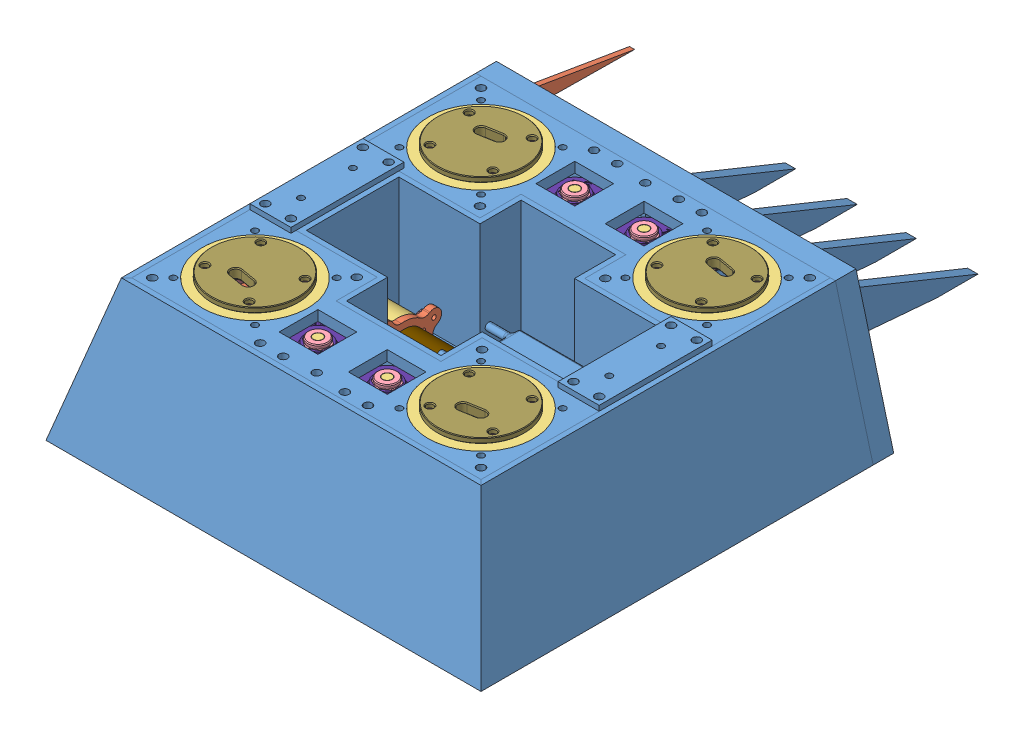
SolidWorks assembly 4WD Swerve Wedge Assembly, configuration Default. Lengths in mm.
Overall size (296.46 104.5 388.68).
183 component instances, 40 part files, 37 mates.
Components (placement in the parent):
- 4WD Swerve Wedge-1: 4WD Swerve Wedge [Default] at origin size (268.87 95.25 382.09)
- Manufacture Ready Swerve_Double Gearbox Wheel_Assem-1: Manufacture Ready Swerve_Double Gearbox Wheel_Assem [Default] at (-69.85 25.4 -69.85) x (-0.171296 0 -0.98522) z (0.98522 0 -0.171296) size (83.94 95.25 79.69)
  - PROPDRIVE 2836-1: PROPDRIVE 2836 [Default] at (-7.34 47.9628 0) x (0 0.80165 -0.597794) z (0 0.597794 0.80165) size (28 45.1 28)
  - Zoro Bearing 50mmID 65mm OD 7mmWidth-1: Zoro Bearing 50mmID 65mm OD 7mmWidth [Default] at (0 63.175 0) x (0.965482 0 -0.260469) z (0.260469 0 0.965482) size (65 7 65)
  - Zoro Bearing 50mmID 65mm OD 7mmWidth-2: Zoro Bearing 50mmID 65mm OD 7mmWidth [Default] at (0 32.075 0) x (0.000165 0 -1) z (1 0 0.000165) size (65 7 65)
  - Double Gearbox 36mm 19 to 1-2: Double Gearbox 36mm 19 to 1 [Default] at (-6.0895 0 0) x (0 0 1) z (0 1 0) size (36 76.01 36)
  - FL696ZZ-1: FL696ZZ [Default] at (30.7875 0 0) x (-1 0 0) z (0 -0.99717 0.07518) size (5 17 17)
  - Casted Swerve Wheel-1: Casted Swerve Wheel [Default] at (-0.4634 0 0) size (26.13 50.8 50.8)
  - Custom Input Shaft Pully-3: Custom Input Shaft Pully [Default] at (20.1995 0 0) x (0 0 1) z (0 1 0) size (19.98 11.18 19.98)
  - 5mm Pully Interface-1: 5mm Pully Interface [Default] at origin size (65.57 21.67 65.57)
  - Bottom Bearing Retainer-1: Bottom Bearing Retainer [Default] at origin size (56.35 4.76 56.35)
  - Drive Motor Face Mount-1: Drive Motor Face Mount [Default] at origin size (2.29 27.26 43.18)
  - Gearbox-Side Support-1: Gearbox-Side Support [Default] at origin size (6.35 34.92 28.57)
  - Inner Modual Lid-1: Inner Modual Lid [Default] at origin size (53.98 6.35 53.98)
  - Innermost Structure-1: Innermost Structure [Default] at origin size (50.34 38.64 53.98)
  - Left Motor Mount Retainer-1: Left Motor Mount Retainer [Default] at origin size (10.68 17.78 8.44)
  - Pully-Side Support-1: Pully-Side Support [Default] at origin size (6.35 34.92 28.57)
  - Wheel Support Mount Plate-1: Wheel Support Mount Plate [Default] at origin size (69.4 4.76 56.35)
  - Left Motor Mount Retainer-2: Left Motor Mount Retainer [Right] at origin size (10.68 17.78 8.44)
  - Custom Motor Output Shaft Pinion-3: Custom Motor Output Shaft Pinion [Default] at (19.431 47.9628 0) x (0 -0.974186 0.225748) z (0 0.225748 0.974186) size (16.43 12.7 16.28)
- 2845 3.17mm 2600kv Surpass-5: 2845 3.17mm 2600kv Surpass [Default] at (-24.11 26.8 0) x (0 -0.462995 0.886361) z (0 -0.886361 -0.462995) size (28 84.78 28)
- OVONIC - 1300mAh - 6S1P-1: OVONIC - 1300mAh - 6S1P [Default] at (41.3 37.465 -21.2725) x (0 1 0) z (1 0 0) size (36.86 42.55 90.17)
- 36mm 47.1(263_1) gear box-1: 36mm 47.1(263_1) gear box [Default] at (-51.547 26.8 0) x (0 0.509483 -0.860481) z (0 0.860481 0.509483) size (52.63 77.16 52.63)
  - 251916mount_36mm gearbox.step-1: 251916mount_36mm gearbox.step [Default] at (0 2.413 0) size (52.63 6.35 52.63)
  - 36mm 47.1(263_1) gear box.step-1: 36mm 47.1(263_1) gear box.step [Default] at origin size (36 45.1 36)
  - 36mm 47.1(263_1) gear box-0.step-1: 36mm 47.1(263_1) gear box-0.step [Default] at origin size (36 10.13 36)
  - 36mm 47.1(263_1) gear box-1.step-1: 36mm 47.1(263_1) gear box-1.step [Default] at origin size (8 20 8)
- Manufacture Ready Swerve_Double Gearbox Wheel_Assem-6: Manufacture Ready Swerve_Double Gearbox Wheel_Assem [Default] at (69.85 25.4 69.85) x (0.171296 0 0.98522) z (-0.98522 0 0.171296) size (83.94 95.25 79.69)
  - PROPDRIVE 2836-1: PROPDRIVE 2836 [Default] at (-7.34 47.9628 0) x (0 0.80165 -0.597794) z (0 0.597794 0.80165) size (28 45.1 28)
  - Zoro Bearing 50mmID 65mm OD 7mmWidth-1: Zoro Bearing 50mmID 65mm OD 7mmWidth [Default] at (0 63.175 0) x (0.965482 0 -0.260469) z (0.260469 0 0.965482) size (65 7 65)
  - Zoro Bearing 50mmID 65mm OD 7mmWidth-2: Zoro Bearing 50mmID 65mm OD 7mmWidth [Default] at (0 32.075 0) x (0.000165 0 -1) z (1 0 0.000165) size (65 7 65)
  - Double Gearbox 36mm 19 to 1-2: Double Gearbox 36mm 19 to 1 [Default] at (-6.0895 0 0) x (0 0 1) z (0 1 0) size (36 76.01 36)
  - FL696ZZ-1: FL696ZZ [Default] at (30.7875 0 0) x (-1 0 0) z (0 -0.99717 0.07518) size (5 17 17)
  - Casted Swerve Wheel-1: Casted Swerve Wheel [Default] at (-0.4634 0 0) size (26.13 50.8 50.8)
  - Custom Input Shaft Pully-3: Custom Input Shaft Pully [Default] at (20.1995 0 0) x (0 0 1) z (0 1 0) size (19.98 11.18 19.98)
  - 5mm Pully Interface-1: 5mm Pully Interface [Default] at origin size (65.57 21.67 65.57)
  - Bottom Bearing Retainer-1: Bottom Bearing Retainer [Default] at origin size (56.35 4.76 56.35)
  - Drive Motor Face Mount-1: Drive Motor Face Mount [Default] at origin size (2.29 27.26 43.18)
  - Gearbox-Side Support-1: Gearbox-Side Support [Default] at origin size (6.35 34.92 28.57)
  - Inner Modual Lid-1: Inner Modual Lid [Default] at origin size (53.98 6.35 53.98)
  - Innermost Structure-1: Innermost Structure [Default] at origin size (50.34 38.64 53.98)
  - Left Motor Mount Retainer-1: Left Motor Mount Retainer [Default] at origin size (10.68 17.78 8.44)
  - Pully-Side Support-1: Pully-Side Support [Default] at origin size (6.35 34.92 28.57)
  - Wheel Support Mount Plate-1: Wheel Support Mount Plate [Default] at origin size (69.4 4.76 56.35)
  - Left Motor Mount Retainer-2: Left Motor Mount Retainer [Right] at origin size (10.68 17.78 8.44)
  - Custom Motor Output Shaft Pinion-3: Custom Motor Output Shaft Pinion [Default] at (19.431 47.9628 0) x (0 -0.974186 0.225748) z (0 0.225748 0.974186) size (16.43 12.7 16.28)
- DartBox V2 6mm Shaft-1: DartBox V2 6mm Shaft [Default] at (-6.022 -10.937 -80.2176) x (-0.054657 0 -0.998505) z (0 1 0) size (21.95 21.95 72.3)
  - DartBox V2 6mm Shaft.stp-1: DartBox V2 6mm Shaft.stp [Default] at origin size (21.95 21.95 72.3)
    - DartBox V2 Drive 6mm Output.stp-1: DartBox V2 Drive 6mm Output.stp [Default] at (0 15.4164 54.362) x (0 1 0) z (0 0 1) size (21.95 21.95 42.9)
      - Ring Gear.stp-1: Ring Gear.stp [Default] at (-10.101 0.0152 -54.1116) x (0 -1 0) z (0 0 1) size (21.95 21.95 40.4)
        - Front Plate.stp-1: Front Plate.stp [Default] at (0.0152 10.101 56.6116) x (0 1 0) z (1 0 0) size (21.95 30.5 21.95)
          - Shaft.stp-1: Shaft.stp [Default] x (-0.819152 0 -0.573576) z (0.573576 0 -0.819152) size (7.4 30.3 6.7)
            - Retaining Ring.stp-1: Retaining Ring.stp [Default] at (0 16.65 0) x (-1 0 0) z (0 -1 0) size (7.4 6.16 0.5)
            - Shaft-0.stp-1: Shaft-0.stp [Default] at origin size (6 30.3 6)
          - Front Plate-1.stp-1: Front Plate-1.stp [Default] at origin size (21.95 6.5 21.95)
          - Front Plate-2.stp-1: Front Plate-2.stp [Default] at origin size (9.5 6 9.5)
        - Ring Gear Body.stp-1: Ring Gear Body.stp [Default] at (0.0152 10.101 56.6116) x (0 1 0) z (1 0 0) size (16.5 10.4 16.5)
      - Motor Mount Plate.stp-1: Motor Mount Plate.stp [Default] at (0 0 2.5) x (1 0 0) z (0 -1 0) size (21.95 3.5 21.95)
      - Screws M2 x 14mm.stp-1: Screws M2 x 14mm.stp [Default] at (6.364 6.364 0.9) size (3.4 3.4 15.61)
      - Screws M2 x 14mm.stp-2: Screws M2 x 14mm.stp [Default] at (-6.364 6.364 0.9) x (0 1 0) z (0 0 1) size (3.4 3.4 15.61)
      - Screws M2 x 14mm.stp-3: Screws M2 x 14mm.stp [Default] at (-6.364 -6.364 0.9) x (-1 0 0) z (0 0 1) size (3.4 3.4 15.61)
      - Screws M2 x 14mm.stp-4: Screws M2 x 14mm.stp [Default] at (6.364 -6.364 0.9) x (0 -1 0) z (0 0 1) size (3.4 3.4 15.61)
    - DartBox 130 motor.stp-1: DartBox 130 motor.stp [Default] at (0 15.4164 54.362) x (1 0 0) z (0 0 -1) size (15.5 20.4 34.9)
- Manufacture Ready Swerve_Double Gearbox Wheel_Assem-8: Manufacture Ready Swerve_Double Gearbox Wheel_Assem [Default] at (69.85 25.4 -69.85) x (0.171296 0 -0.98522) z (0.98522 0 0.171296) size (83.94 95.25 79.69)
  - PROPDRIVE 2836-1: PROPDRIVE 2836 [Default] at (-7.34 47.9628 0) x (0 0.80165 -0.597794) z (0 0.597794 0.80165) size (28 45.1 28)
  - Zoro Bearing 50mmID 65mm OD 7mmWidth-1: Zoro Bearing 50mmID 65mm OD 7mmWidth [Default] at (0 63.175 0) x (0.965482 0 -0.260469) z (0.260469 0 0.965482) size (65 7 65)
  - Zoro Bearing 50mmID 65mm OD 7mmWidth-2: Zoro Bearing 50mmID 65mm OD 7mmWidth [Default] at (0 32.075 0) x (0.000165 0 -1) z (1 0 0.000165) size (65 7 65)
  - Double Gearbox 36mm 19 to 1-2: Double Gearbox 36mm 19 to 1 [Default] at (-6.0895 0 0) x (0 0 1) z (0 1 0) size (36 76.01 36)
  - FL696ZZ-1: FL696ZZ [Default] at (30.7875 0 0) x (-1 0 0) z (0 -0.99717 0.07518) size (5 17 17)
  - Casted Swerve Wheel-1: Casted Swerve Wheel [Default] at (-0.4634 0 0) size (26.13 50.8 50.8)
  - Custom Input Shaft Pully-3: Custom Input Shaft Pully [Default] at (20.1995 0 0) x (0 0 1) z (0 1 0) size (19.98 11.18 19.98)
  - 5mm Pully Interface-1: 5mm Pully Interface [Default] at origin size (65.57 21.67 65.57)
  - Bottom Bearing Retainer-1: Bottom Bearing Retainer [Default] at origin size (56.35 4.76 56.35)
  - Drive Motor Face Mount-1: Drive Motor Face Mount [Default] at origin size (2.29 27.26 43.18)
  - Gearbox-Side Support-1: Gearbox-Side Support [Default] at origin size (6.35 34.92 28.57)
  - Inner Modual Lid-1: Inner Modual Lid [Default] at origin size (53.98 6.35 53.98)
  - Innermost Structure-1: Innermost Structure [Default] at origin size (50.34 38.64 53.98)
  - Left Motor Mount Retainer-1: Left Motor Mount Retainer [Default] at origin size (10.68 17.78 8.44)
  - Pully-Side Support-1: Pully-Side Support [Default] at origin size (6.35 34.92 28.57)
  - Wheel Support Mount Plate-1: Wheel Support Mount Plate [Default] at origin size (69.4 4.76 56.35)
  - Left Motor Mount Retainer-2: Left Motor Mount Retainer [Right] at origin size (10.68 17.78 8.44)
  - Custom Motor Output Shaft Pinion-3: Custom Motor Output Shaft Pinion [Default] at (19.431 47.9628 0) x (0 -0.974186 0.225748) z (0 0.225748 0.974186) size (16.43 12.7 16.28)
- DartBox V2 6mm Shaft-2: DartBox V2 6mm Shaft [Default] at (36.8087 -10.937 -78.5324) x (0.054657 0 -0.998505) z (0 1 0) size (21.95 21.95 72.3)
  - DartBox V2 6mm Shaft.stp-1: DartBox V2 6mm Shaft.stp [Default] at origin size (21.95 21.95 72.3)
    - DartBox V2 Drive 6mm Output.stp-1: DartBox V2 Drive 6mm Output.stp [Default] at (0 15.4164 54.362) x (0 1 0) z (0 0 1) size (21.95 21.95 42.9)
      - Ring Gear.stp-1: Ring Gear.stp [Default] at (-10.101 0.0152 -54.1116) x (0 -1 0) z (0 0 1) size (21.95 21.95 40.4)
        - Front Plate.stp-1: Front Plate.stp [Default] at (0.0152 10.101 56.6116) x (0 1 0) z (1 0 0) size (21.95 30.5 21.95)
          - Shaft.stp-1: Shaft.stp [Default] x (-0.819152 0 -0.573576) z (0.573576 0 -0.819152) size (7.4 30.3 6.7)
            - Retaining Ring.stp-1: Retaining Ring.stp [Default] at (0 16.65 0) x (-1 0 0) z (0 -1 0) size (7.4 6.16 0.5)
            - Shaft-0.stp-1: Shaft-0.stp [Default] at origin size (6 30.3 6)
          - Front Plate-1.stp-1: Front Plate-1.stp [Default] at origin size (21.95 6.5 21.95)
          - Front Plate-2.stp-1: Front Plate-2.stp [Default] at origin size (9.5 6 9.5)
        - Ring Gear Body.stp-1: Ring Gear Body.stp [Default] at (0.0152 10.101 56.6116) x (0 1 0) z (1 0 0) size (16.5 10.4 16.5)
      - Motor Mount Plate.stp-1: Motor Mount Plate.stp [Default] at (0 0 2.5) x (1 0 0) z (0 -1 0) size (21.95 3.5 21.95)
      - Screws M2 x 14mm.stp-1: Screws M2 x 14mm.stp [Default] at (6.364 6.364 0.9) size (3.4 3.4 15.61)
      - Screws M2 x 14mm.stp-2: Screws M2 x 14mm.stp [Default] at (-6.364 6.364 0.9) x (0 1 0) z (0 0 1) size (3.4 3.4 15.61)
      - Screws M2 x 14mm.stp-3: Screws M2 x 14mm.stp [Default] at (-6.364 -6.364 0.9) x (-1 0 0) z (0 0 1) size (3.4 3.4 15.61)
      - Screws M2 x 14mm.stp-4: Screws M2 x 14mm.stp [Default] at (6.364 -6.364 0.9) x (0 -1 0) z (0 0 1) size (3.4 3.4 15.61)
    - DartBox 130 motor.stp-1: DartBox 130 motor.stp [Default] at (0 15.4164 54.362) x (1 0 0) z (0 0 -1) size (15.5 20.4 34.9)
- Manufacture Ready Swerve_Double Gearbox Wheel_Assem-9: Manufacture Ready Swerve_Double Gearbox Wheel_Assem [Default] at (-69.85 25.4 69.85) x (-0.171296 0 0.98522) z (-0.98522 0 -0.171296) size (83.94 95.25 79.69)
  - PROPDRIVE 2836-1: PROPDRIVE 2836 [Default] at (-7.34 47.9628 0) x (0 0.80165 -0.597794) z (0 0.597794 0.80165) size (28 45.1 28)
  - Zoro Bearing 50mmID 65mm OD 7mmWidth-1: Zoro Bearing 50mmID 65mm OD 7mmWidth [Default] at (0 63.175 0) x (0.965482 0 -0.260469) z (0.260469 0 0.965482) size (65 7 65)
  - Zoro Bearing 50mmID 65mm OD 7mmWidth-2: Zoro Bearing 50mmID 65mm OD 7mmWidth [Default] at (0 32.075 0) x (0.000165 0 -1) z (1 0 0.000165) size (65 7 65)
  - Double Gearbox 36mm 19 to 1-2: Double Gearbox 36mm 19 to 1 [Default] at (-6.0895 0 0) x (0 0 1) z (0 1 0) size (36 76.01 36)
  - FL696ZZ-1: FL696ZZ [Default] at (30.7875 0 0) x (-1 0 0) z (0 -0.99717 0.07518) size (5 17 17)
  - Casted Swerve Wheel-1: Casted Swerve Wheel [Default] at (-0.4634 0 0) size (26.13 50.8 50.8)
  - Custom Input Shaft Pully-3: Custom Input Shaft Pully [Default] at (20.1995 0 0) x (0 0 1) z (0 1 0) size (19.98 11.18 19.98)
  - 5mm Pully Interface-1: 5mm Pully Interface [Default] at origin size (65.57 21.67 65.57)
  - Bottom Bearing Retainer-1: Bottom Bearing Retainer [Default] at origin size (56.35 4.76 56.35)
  - Drive Motor Face Mount-1: Drive Motor Face Mount [Default] at origin size (2.29 27.26 43.18)
  - Gearbox-Side Support-1: Gearbox-Side Support [Default] at origin size (6.35 34.92 28.57)
  - Inner Modual Lid-1: Inner Modual Lid [Default] at origin size (53.98 6.35 53.98)
  - Innermost Structure-1: Innermost Structure [Default] at origin size (50.34 38.64 53.98)
  - Left Motor Mount Retainer-1: Left Motor Mount Retainer [Default] at origin size (10.68 17.78 8.44)
  - Pully-Side Support-1: Pully-Side Support [Default] at origin size (6.35 34.92 28.57)
  - Wheel Support Mount Plate-1: Wheel Support Mount Plate [Default] at origin size (69.4 4.76 56.35)
  - Left Motor Mount Retainer-2: Left Motor Mount Retainer [Right] at origin size (10.68 17.78 8.44)
  - Custom Motor Output Shaft Pinion-3: Custom Motor Output Shaft Pinion [Default] at (19.431 47.9628 0) x (0 -0.974186 0.225748) z (0 0.225748 0.974186) size (16.43 12.7 16.28)
- DartBox V2 6mm Shaft-3: DartBox V2 6mm Shaft [Default] at (-36.8087 -10.937 78.5324) x (-0.054657 0 0.998505) z (0 1 0) size (21.95 21.95 72.3)
  - DartBox V2 6mm Shaft.stp-1: DartBox V2 6mm Shaft.stp [Default] at origin size (21.95 21.95 72.3)
    - DartBox V2 Drive 6mm Output.stp-1: DartBox V2 Drive 6mm Output.stp [Default] at (0 15.4164 54.362) x (0 1 0) z (0 0 1) size (21.95 21.95 42.9)
      - Ring Gear.stp-1: Ring Gear.stp [Default] at (-10.101 0.0152 -54.1116) x (0 -1 0) z (0 0 1) size (21.95 21.95 40.4)
        - Front Plate.stp-1: Front Plate.stp [Default] at (0.0152 10.101 56.6116) x (0 1 0) z (1 0 0) size (21.95 30.5 21.95)
          - Shaft.stp-1: Shaft.stp [Default] x (-0.819152 0 -0.573576) z (0.573576 0 -0.819152) size (7.4 30.3 6.7)
            - Retaining Ring.stp-1: Retaining Ring.stp [Default] at (0 16.65 0) x (-1 0 0) z (0 -1 0) size (7.4 6.16 0.5)
            - Shaft-0.stp-1: Shaft-0.stp [Default] at origin size (6 30.3 6)
          - Front Plate-1.stp-1: Front Plate-1.stp [Default] at origin size (21.95 6.5 21.95)
          - Front Plate-2.stp-1: Front Plate-2.stp [Default] at origin size (9.5 6 9.5)
        - Ring Gear Body.stp-1: Ring Gear Body.stp [Default] at (0.0152 10.101 56.6116) x (0 1 0) z (1 0 0) size (16.5 10.4 16.5)
      - Motor Mount Plate.stp-1: Motor Mount Plate.stp [Default] at (0 0 2.5) x (1 0 0) z (0 -1 0) size (21.95 3.5 21.95)
      - Screws M2 x 14mm.stp-1: Screws M2 x 14mm.stp [Default] at (6.364 6.364 0.9) size (3.4 3.4 15.61)
      - Screws M2 x 14mm.stp-2: Screws M2 x 14mm.stp [Default] at (-6.364 6.364 0.9) x (0 1 0) z (0 0 1) size (3.4 3.4 15.61)
      - Screws M2 x 14mm.stp-3: Screws M2 x 14mm.stp [Default] at (-6.364 -6.364 0.9) x (-1 0 0) z (0 0 1) size (3.4 3.4 15.61)
      - Screws M2 x 14mm.stp-4: Screws M2 x 14mm.stp [Default] at (6.364 -6.364 0.9) x (0 -1 0) z (0 0 1) size (3.4 3.4 15.61)
    - DartBox 130 motor.stp-1: DartBox 130 motor.stp [Default] at (0 15.4164 54.362) x (1 0 0) z (0 0 -1) size (15.5 20.4 34.9)
- DartBox V2 6mm Shaft-4: DartBox V2 6mm Shaft [Default] at (6.022 -10.937 80.2176) x (0.054657 0 0.998505) z (0 1 0) size (21.95 21.95 72.3)
  - DartBox V2 6mm Shaft.stp-1: DartBox V2 6mm Shaft.stp [Default] at origin size (21.95 21.95 72.3)
    - DartBox V2 Drive 6mm Output.stp-1: DartBox V2 Drive 6mm Output.stp [Default] at (0 15.4164 54.362) x (0 1 0) z (0 0 1) size (21.95 21.95 42.9)
      - Ring Gear.stp-1: Ring Gear.stp [Default] at (-10.101 0.0152 -54.1116) x (0 -1 0) z (0 0 1) size (21.95 21.95 40.4)
        - Front Plate.stp-1: Front Plate.stp [Default] at (0.0152 10.101 56.6116) x (0 1 0) z (1 0 0) size (21.95 30.5 21.95)
          - Shaft.stp-1: Shaft.stp [Default] x (-0.819152 0 -0.573576) z (0.573576 0 -0.819152) size (7.4 30.3 6.7)
            - Retaining Ring.stp-1: Retaining Ring.stp [Default] at (0 16.65 0) x (-1 0 0) z (0 -1 0) size (7.4 6.16 0.5)
            - Shaft-0.stp-1: Shaft-0.stp [Default] at origin size (6 30.3 6)
          - Front Plate-1.stp-1: Front Plate-1.stp [Default] at origin size (21.95 6.5 21.95)
          - Front Plate-2.stp-1: Front Plate-2.stp [Default] at origin size (9.5 6 9.5)
        - Ring Gear Body.stp-1: Ring Gear Body.stp [Default] at (0.0152 10.101 56.6116) x (0 1 0) z (1 0 0) size (16.5 10.4 16.5)
      - Motor Mount Plate.stp-1: Motor Mount Plate.stp [Default] at (0 0 2.5) x (1 0 0) z (0 -1 0) size (21.95 3.5 21.95)
      - Screws M2 x 14mm.stp-1: Screws M2 x 14mm.stp [Default] at (6.364 6.364 0.9) size (3.4 3.4 15.61)
      - Screws M2 x 14mm.stp-2: Screws M2 x 14mm.stp [Default] at (-6.364 6.364 0.9) x (0 1 0) z (0 0 1) size (3.4 3.4 15.61)
      - Screws M2 x 14mm.stp-3: Screws M2 x 14mm.stp [Default] at (-6.364 -6.364 0.9) x (-1 0 0) z (0 0 1) size (3.4 3.4 15.61)
      - Screws M2 x 14mm.stp-4: Screws M2 x 14mm.stp [Default] at (6.364 -6.364 0.9) x (0 -1 0) z (0 0 1) size (3.4 3.4 15.61)
    - DartBox 130 motor.stp-1: DartBox 130 motor.stp [Default] at (0 15.4164 54.362) x (1 0 0) z (0 0 -1) size (15.5 20.4 34.9)
- 36mm goBILDA motor clamp-1: 36mm goBILDA motor clamp [Default] at (-83.0172 32.3593 -30.3345) x (0 0 -1) z (-1 0 0) size (46.17 45 8)
  - 1400-0032-0036.STEP-1: 1400-0032-0036.STEP [Default] at (-30.3345 5.5593 8.2328) size (46.17 45 8)
  - 2800-0004-0012_90128A207.STEP-1: 2800-0004-0012_90128A207.STEP [Default] at (-8.6623 -1.4407 12.2328) x (1 0 0) z (0 -1 0) size (7 7 16.01)
- RB Standoff_-1: RB Standoff_ [1000L] at (-103.1875 73.025 -30.1625) size (9.53 25.4 9.53)
- RB Standoff_-2: RB Standoff_ [1000L] at (-87.3125 73.025 -30.1625) size (9.53 25.4 9.53)
- RB Standoff_-3: RB Standoff_ [1000L] at (87.3125 73.025 -30.1625) x (-1 0 0) z (0 0 -1) size (9.53 25.4 9.53)
- RB Standoff_-4: RB Standoff_ [1000L] at (103.1875 73.025 -30.1625) x (-1 0 0) z (0 0 -1) size (9.53 25.4 9.53)
- RB Standoff_-5: RB Standoff_ [1000L] at (103.1875 73.025 30.1625) x (-1 0 0) z (0 0 -1) size (9.53 25.4 9.53)
- RB Standoff_-6: RB Standoff_ [1000L] at (87.3125 73.025 30.1625) x (-1 0 0) z (0 0 -1) size (9.53 25.4 9.53)
- RB Standoff_-7: RB Standoff_ [1000L] at (-87.3125 73.025 30.1625) size (9.53 25.4 9.53)
- RB Standoff_-8: RB Standoff_ [1000L] at (-103.1875 73.025 30.1625) size (9.53 25.4 9.53)
- Proto Swerve Turn Pinion 5mm HTD Pulley-1: Proto Swerve Turn Pinion 5mm HTD Pulley [Default] at (-21.4153 73.9232 -79.375) x (0.825312 0 -0.564678) z (0.564678 0 0.825312) size (31.44 23.6 31.44)
- Proto Swerve Turn Pinion 5mm HTD Pulley-2: Proto Swerve Turn Pinion 5mm HTD Pulley [Default] at (21.4153 73.9232 -79.375) x (0.825312 0 0.564678) z (-0.564678 0 0.825312) size (31.44 23.6 31.44)
- Proto Swerve Turn Pinion 5mm HTD Pulley-3: Proto Swerve Turn Pinion 5mm HTD Pulley [Default] at (21.4153 73.9232 79.375) x (-0.825312 0 0.564678) z (-0.564678 0 -0.825312) size (31.44 23.6 31.44)
- Proto Swerve Turn Pinion 5mm HTD Pulley-4: Proto Swerve Turn Pinion 5mm HTD Pulley [Default] at (-21.4153 73.9232 79.375) x (-0.825312 0 -0.564678) z (0.564678 0 -0.825312) size (31.44 23.6 31.44)
- RB Standoff_-11: RB Standoff_ [1000L] at (-38.7415 73.025 -38.1) x (0.918365 0 -0.395734) z (0.395734 0 0.918365) size (9.53 25.4 9.53)
- RB Standoff_-14: RB Standoff_ [1000L] at (38.7415 73.025 -38.1) x (-0.918365 0 -0.395734) z (0.395734 0 -0.918365) size (9.53 25.4 9.53)
- RB Standoff_-17: RB Standoff_ [1000L] at (-38.7415 73.025 38.1) x (0.918365 0 0.395734) z (-0.395734 0 0.918365) size (9.53 25.4 9.53)
- RB Standoff_-19: RB Standoff_ [1000L] at (38.7415 73.025 38.1) x (-0.918365 0 0.395734) z (-0.395734 0 -0.918365) size (9.53 25.4 9.53)
- T81H-RM41.stp-1: T81H-RM41.stp [Default] at (-113.125 26.8 0) x (0 0.870146 -0.492795) z (-1 0 0) size (20.32 20.32 20.32)
- 0.375in_Medium_NutStrip_2x2_R1.step_Custom-1: 0.375in_Medium_NutStrip_2x2_R1.step_Custom [Default] at (14.2875 49.2125 -103.1875) x (0 0 1) z (-1 0 0) size (9.53 9.53 28.97)
- 0.375in_Medium_NutStrip_2x2_R1.step_Custom-2: 0.375in_Medium_NutStrip_2x2_R1.step_Custom [Default] at (-14.2875 49.2125 -103.1875) x (0 0 -1) z (1 0 0) size (9.53 9.53 28.97)
- 4wd Swerve Finger-1: 4wd Swerve Finger [Default] at (-115.665 26.8 0) x (0 0.011579 0.999933) z (0 -0.999933 0.011579) size (276.45 46.36 44.9)
- AS5600 Encoder Magnet-1: AS5600 Encoder Magnet [Default] at (-21.4153 88.2942 -79.375) size (6 2.5 6)
- Custom Motor Output Shaft-1: Custom Motor Output Shaft [Default] at (-21.4153 76.2346 -79.375) x (0.432402 0 -0.901681) z (0 -1 0) size (12.7 13.75 26.62)
- Custom Motor Output Shaft-2: Custom Motor Output Shaft [Default] at (21.4153 76.2346 -79.375) x (-0.432402 0 -0.901681) z (0 1 0) size (12.7 13.75 26.62)
- AS5600 Encoder Magnet-2: AS5600 Encoder Magnet [Default] at (21.4153 88.2942 -79.375) x (-1 0 0) z (0 0 -1) size (6 2.5 6)
- AS5600 Encoder Magnet-3: AS5600 Encoder Magnet [Default] at (-21.4153 88.2942 79.375) size (6 2.5 6)
- Custom Motor Output Shaft-3: Custom Motor Output Shaft [Default] at (-21.4153 76.2346 79.375) x (0.432402 0 0.901681) z (0 1 0) size (12.7 13.75 26.62)
- AS5600 Encoder Magnet-4: AS5600 Encoder Magnet [Default] at (21.4153 88.2942 79.375) x (-1 0 0) z (0 0 -1) size (6 2.5 6)
- Custom Motor Output Shaft-4: Custom Motor Output Shaft [Default] at (21.4153 76.2346 79.375) x (-0.432402 0 0.901681) z (0 -1 0) size (12.7 13.75 26.62)
Mates (geometry in assembly coordinates):
- Coincident1: coincident aligned: plane of 4WD Swerve Wedge-1 through (0 0 0) normal (0 0 1)
- Coincident2: coincident aligned: plane of 4WD Swerve Wedge-1 through (0 0 0) normal (0 1 0)
- Coincident3: coincident aligned: plane of 4WD Swerve Wedge-1 through (0 0 0) normal (1 0 0)
- Coincident4: coincident aligned: plane of 4WD Swerve Wedge-1 through (0 92.075 0) normal (0 1 0); plane of Manufacture Ready Swerve_Double Gearbox Wheel_Assem-1/Zoro Bearing 50mmID 65mm OD 7mmWidth-1 through (-69.85 92.075 -69.85) normal (0 1 0)
- Concentric1: concentric anti-aligned: cylinder of 4WD Swerve Wedge-1 through (-69.85 85.725 -69.85) axis (0 1 0) radius 32.5; cylinder of Manufacture Ready Swerve_Double Gearbox Wheel_Assem-1/Zoro Bearing 50mmID 65mm OD 7mmWidth-1 through (-69.85 92.075 -69.85) axis (0 -1 0) radius 32.5
- Coincident10: coincident anti-aligned: plane of 2845 3.17mm 2600kv Surpass-5 through (-47.61 26.8 0) normal (-1 0 0); plane of 36mm 47.1(263_1) gear box-1/251916mount_36mm gearbox.step-1 through (-47.61 26.8 0) normal (1 0 0)
- Concentric3: concentric aligned: cylinder of 2845 3.17mm 2600kv Surpass-5 through (-24.11 26.8 0) axis (-1 0 0) radius 14; cylinder of 36mm 47.1(263_1) gear box-1/36mm 47.1(263_1) gear box.step-1 through (-51.547 26.8 0) axis (-1 0 0) radius 18
- Coincident12: coincident: line of 4WD Swerve Wedge-1 through (-104.775 0 14.825) axis (0 0 -1); plane of 36mm 47.1(263_1) gear box-1/36mm 47.1(263_1) gear box-0.step-1 through (-104.775 26.8 0) normal (-1 0 0)
- Coincident18: coincident aligned: plane of 4WD Swerve Wedge-1 through (0 60.325 0) normal (0 1 0); plane of DartBox V2 6mm Shaft-1/DartBox V2 6mm Shaft.stp-1/DartBox V2 Drive 6mm Output.stp-1/Ring Gear.stp-1/Front Plate.stp-1/Front Plate-1.stp-1 through (-21.4153 60.325 -79.375) normal (0 1 0)
- Concentric6: concentric aligned: cylinder of DartBox V2 6mm Shaft-1/DartBox V2 6mm Shaft.stp-1/DartBox V2 Drive 6mm Output.stp-1/Ring Gear.stp-1/Front Plate.stp-1/Front Plate-1.stp-1 through (-21.4153 56.325 -79.375) axis (0 1 0) radius 10.975; cylinder of 4WD Swerve Wedge-1 through (-21.4153 53.975 -79.375) axis (0 1 0) radius 10.9728
- Coincident19: coincident anti-aligned: plane of 4WD Swerve Wedge-1 through (0 50.8 0) normal (0 -1 0); plane of 36mm goBILDA motor clamp-1/1400-0032-0036.STEP-1 through (-99.25 50.8 19) normal (0 1 0)
- Concentric7: concentric anti-aligned: cylinder of 4WD Swerve Wedge-1 through (-95.25 92.076 16) axis (0 -1 0) radius 2; cylinder of 36mm goBILDA motor clamp-1/1400-0032-0036.STEP-1 through (-95.25 50.8 16) axis (0 1 0) radius 1.65
- Concentric8: concentric aligned: cylinder of 4WD Swerve Wedge-1 through (-95.25 53.974 -16) axis (0 1 0) radius 2; cylinder of 36mm goBILDA motor clamp-1/1400-0032-0036.STEP-1 through (-95.25 50.8 -16) axis (0 1 0) radius 1.65
- Concentric9: concentric anti-aligned: cylinder of 36mm 47.1(263_1) gear box-1/36mm 47.1(263_1) gear box.step-1 through (-51.547 26.8 0) axis (-1 0 0) radius 18; cylinder of 36mm goBILDA motor clamp-1/1400-0032-0036.STEP-1 through (-99.25 26.8 0) axis (1 0 0) radius 18
- Distance1: distance = 3.175 mm anti-aligned: plane of OVONIC - 1300mAh - 6S1P-1 through (2.565 19.05 21.2725) normal (-1 0 0); plane of 2845 3.17mm 2600kv Surpass-5 through (-0.61 26.8 0) normal (1 0 0)
- Width1: width aligned: plane of OVONIC - 1300mAh - 6S1P-1 through (41.3 37.465 21.2725) normal (0 0 1); plane of 4WD Swerve Wedge-1 through (41.3 37.465 -21.2725) normal (0 0 -1); plane of OVONIC - 1300mAh - 6S1P-1 through (-107.95 60.325 -31.75) normal (0 0 1); plane of 4WD Swerve Wedge-1 through (107.95 60.325 31.75) normal (0 0 -1)
- Concentric10: concentric aligned: cylinder of 4WD Swerve Wedge-1 through (-103.1875 50.8 -30.1625) axis (0 -1 0) radius 2.5527; cylinder of RB Standoff_-1 through (-103.1875 85.725 -30.1625) axis (0 -1 0) radius 4.7625
- Coincident22: coincident anti-aligned: plane of 4WD Swerve Wedge-1 through (0 60.325 0) normal (0 1 0); plane of RB Standoff_-1 through (-103.1875 60.325 -30.1625) normal (0 -1 0)
- Concentric11: concentric aligned: cylinder of 4WD Swerve Wedge-1 through (-87.3125 50.8 -30.1625) axis (0 -1 0) radius 2.5527; cylinder of RB Standoff_-2 through (-87.3125 85.725 -30.1625) axis (0 -1 0) radius 4.7625
- Coincident23: coincident anti-aligned: plane of 4WD Swerve Wedge-1 through (0 60.325 0) normal (0 1 0); plane of RB Standoff_-2 through (-87.3125 60.325 -30.1625) normal (0 -1 0)
- Coincident26: coincident anti-aligned: plane of 4WD Swerve Wedge-1 through (0 60.325 0) normal (0 1 0); plane of RB Standoff_-11 through (-38.7415 60.325 -38.1) normal (0 -1 0)
- Concentric14: concentric anti-aligned: cylinder of 4WD Swerve Wedge-1 through (-38.7415 53.975 -38.1) axis (0 1 0) radius 2.5527; cylinder of RB Standoff_-11 through (-38.7415 85.725 -38.1) axis (0 -1 0) radius 4.7625
- Concentric16: concentric anti-aligned: cylinder of 36mm 47.1(263_1) gear box-1/36mm 47.1(263_1) gear box-1.step-1 through (-104.775 26.8 0) axis (-1 0 0) radius 4; line of T81H-RM41.stp-1 through (-134.461 26.8 0) axis (1 0 0)
- Distance3: distance = 6.35 mm aligned: plane of T81H-RM41.stp-1 through (-113.125 26.8 0) normal (-1 0 0); plane of 36mm 47.1(263_1) gear box-1/36mm 47.1(263_1) gear box-0.step-1 through (-106.775 26.8 0) normal (-1 0 0)
- Coincident30: coincident anti-aligned: plane of 4WD Swerve Wedge-1 through (0 19.05 0) normal (0 1 0); plane of OVONIC - 1300mAh - 6S1P-1 through (2.565 19.05 21.2725) normal (0 -1 0)
- Coincident31: coincident anti-aligned: plane of 4WD Swerve Wedge-1 through (0 53.975 0) normal (0 -1 0); plane of 0.375in_Medium_NutStrip_2x2_R1.step_Custom-1 through (79.944 53.975 -98.425) normal (0 1 0)
- Concentric19: concentric anti-aligned: cylinder of 4WD Swerve Wedge-1 through (19.05 92.075 -103.1875) axis (0 -1 0) radius 2.5527; cylinder of 0.375in_Medium_NutStrip_2x2_R1.step_Custom-1 through (19.05 53.975 -103.1875) axis (0 1 0) radius 1.8986
- Concentric20: concentric anti-aligned: cylinder of 4WD Swerve Wedge-1 through (33.3375 92.075 -103.1875) axis (0 -1 0) radius 2.5527; cylinder of 0.375in_Medium_NutStrip_2x2_R1.step_Custom-1 through (33.3375 53.975 -103.1875) axis (0 1 0) radius 1.8986
- Concentric21: concentric aligned: line of T81H-RM41.stp-1 through (-134.461 26.8 0) axis (1 0 0); cylinder of 4wd Swerve Finger-1 through (-133.445 26.8 0) axis (1 0 0) radius 9.525
- Tangent2: tangent: plane of assembly; face of T81H-RM41.stp-1; plane of 4wd Swerve Finger-1 through (-133.445 26.8 0) normal (-1 0 0)
- Concentric22: concentric anti-aligned: cylinder of DartBox V2 6mm Shaft-1/DartBox V2 6mm Shaft.stp-1/DartBox V2 Drive 6mm Output.stp-1/Ring Gear.stp-1/Front Plate.stp-1/Shaft.stp-1/Shaft-0.stp-1 through (-21.4153 62.325 -79.375) axis (0 1 0) radius 3; cylinder of Custom Motor Output Shaft-1 through (-21.4153 89.5442 -79.375) axis (0 -1 0) radius 2.9972
- Coincident32: coincident anti-aligned: plane of DartBox V2 6mm Shaft-1/DartBox V2 6mm Shaft.stp-1/DartBox V2 Drive 6mm Output.stp-1/Ring Gear.stp-1/Front Plate.stp-1/Shaft.stp-1/Retaining Ring.stp-1 through (-21.4153 62.925 -79.375) normal (0 1 0); plane of Custom Motor Output Shaft-1 through (-16.1477 62.925 -76.8489) normal (0 -1 0)
- Concentric23: concentric anti-aligned: cylinder of Proto Swerve Turn Pinion 5mm HTD Pulley-1 through (-21.4153 86.0212 -79.375) axis (0 1 0) radius 15.7209; cylinder of Custom Motor Output Shaft-1 through (-21.4153 89.5442 -79.375) axis (0 -1 0) radius 2.9972
- Coincident36: coincident anti-aligned: plane of Proto Swerve Turn Pinion 5mm HTD Pulley-1 through (-15.3639 84.4388 -83.5154) normal (-0.99708 0 0.076369); plane of Custom Motor Output Shaft-1 through (-15.2855 65.465 -82.4926) normal (0.99708 0 -0.076369)
- Coincident37: coincident aligned: plane of Proto Swerve Turn Pinion 5mm HTD Pulley-1 through (-21.4153 87.0042 -79.375) normal (0 1 0); plane of Custom Motor Output Shaft-1 through (-21.4153 87.0042 -79.375) normal (0 1 0)
- Coincident38: coincident aligned: plane of AS5600 Encoder Magnet-1 through (-21.4153 89.5442 -79.375) normal (0 1 0); plane of Custom Motor Output Shaft-1 through (-16.1477 89.5442 -76.8489) normal (0 1 0)
- Concentric24: concentric aligned: cylinder of AS5600 Encoder Magnet-1 through (-21.4153 89.5442 -79.375) axis (0 -1 0) radius 3; cylinder of Custom Motor Output Shaft-1 through (-21.4153 89.5442 -79.375) axis (0 -1 0) radius 2.9972
